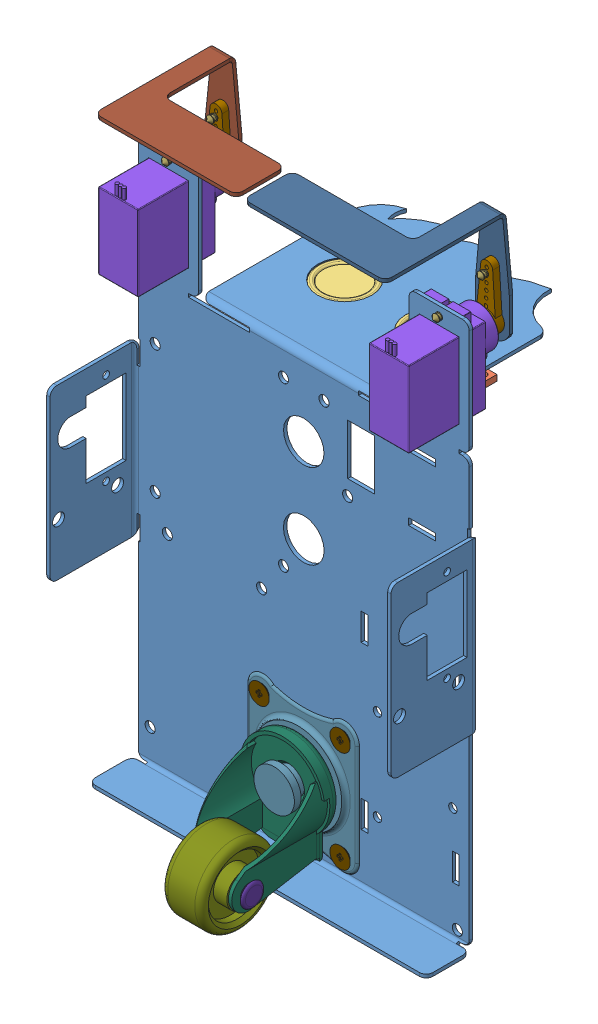
SolidWorks assembly Ensamblaje3, configuration Predeterminado. Lengths in mm.
Overall size (151 194.25 91.61).
41 component instances, 18 part files, 9 mates.
Components (placement in the parent):
- DYOR_MetalSheet_Pusher-1: DYOR_MetalSheet_Pusher [Predeterminado] at (90.3982 -139.1144 139.7994) size (151 194.25 79.67)
- HC-SR04 Ping Sensor-1: HC-SR04 Ping Sensor [Default] at (150.4372 -204.3854 114.6556) x (0 0 -1) z (0 1 0) size (25.18 45 18.07)
  - PCB-1: PCB [Default] at origin size (20.5 45 1.75)
  - Transducer-1: Transducer [Default] at (0 -13.16 13.25) x (1 0 0) z (0 -1 0) size (15.88 12 15.88)
  - Transducer-2: Transducer [Default] at (0 12.34 13.25) x (1 0 0) z (0 -1 0) size (15.88 12 15.88)
  - 3 Pin Header 90 Degree-1: 3 Pin Header 90 Degree [Default] at (8.4275 0 -1.25) x (-1 0 0) z (0 -1 0) size (8 7.82 10)
  - 14 Pin SMT-1: 14 Pin SMT [Default] at (-0.35 -18.5 -0.85) x (0 -1 0) z (1 0 0) size (6 1.6 8.8)
  - 14 Pin SMT-2: 14 Pin SMT [Default] at (0 -0.3826 -0.85) x (1 0 0) z (0 1 0) size (6 1.6 8.8)
  - 14 Pin SMT-3: 14 Pin SMT [Default] at (0 17.5274 -0.85) x (1 0 0) z (0 1 0) size (6 1.6 8.8)
  - Cap1 SMT-1: Cap1 SMT [Default] at (-1.755 7.4774 -0.9689) x (0 1 0) z (-1 0 0) size (4.5 1.84 1.75)
  - Cap1 SMT-2: Cap1 SMT [Default] at (6.835 7.4774 -0.9689) x (0 1 0) z (-1 0 0) size (4.5 1.84 1.75)
  - Cap1 SMT-3: Cap1 SMT [Default] at (-6.835 7.4774 -0.9689) x (0 1 0) z (-1 0 0) size (4.5 1.84 1.75)
  - Cap1 SMT-4: Cap1 SMT [Default] at (4.295 7.4774 -0.9689) x (0 1 0) z (-1 0 0) size (4.5 1.84 1.75)
  - Cap1 SMT-5: Cap1 SMT [Default] at (1.755 7.4774 -0.9689) x (0 1 0) z (-1 0 0) size (4.5 1.84 1.75)
  - Cap1 SMT-6: Cap1 SMT [Default] at (-4.295 7.4774 -0.9689) x (0 1 0) z (-1 0 0) size (4.5 1.84 1.75)
  - HC-SR04 Crystal-1: HC-SR04 Crystal [Default] at (-8.3 0 1.75) x (0 -1 0) z (0 0 1) size (10 3.5 2.7)
- PU-1: PU [Predeterminado] at (-16.2984 3.5 -1.0225) size (91.94 49.57 37.38)
  - sg90-1: sg90 [Default] at (201.5956 -166.7354 155.7219) x (0 -1 0) z (1 0 0) size (31.9 29.9 11.8)
  - sg90-2: sg90 [Default] at (121.452 -166.7354 155.7219) x (0 -1 0) z (1 0 0) size (31.9 29.9 11.8)
  - SG90 plastic Horn-1: SG90 plastic Horn [Default] at (127.352 -172.6354 127.0219) x (0.017141 0.999853 0) z (-0.999853 0.017141 0) size (19.4 4 7.07)
  - SG90 plastic Horn-2: SG90 plastic Horn [Default] at (207.4956 -172.6354 127.0219) x (0.020276 0.999794 0) z (-0.999794 0.020276 0) size (19.4 4 7.07)
  - Pusher_left-1: Pusher_left [Predeterminado] at (252.6438 -158.8738 124.0219) x (-1 0 0) z (0 0 -1) size (44 33.65 35.77)
  - Pusher_right-1: Pusher_right [Predeterminado] at (82.2037 -158.8738 125.0219) size (44 33.65 35.77)
  - M2x6 SelfTap Screw-1: M2x6 SelfTap Screw [Predeterminado] at (207.4956 -164.3354 136.8219) x (-0.923728 -0.383049 0) z (0 0 -1) size (3.4 3.28 6)
  - M2x6 SelfTap Screw-2: M2x6 SelfTap Screw [Predeterminado] at (207.4956 -191.6354 136.3219) x (-0.923728 -0.383049 0) z (0 0 -1) size (3.4 3.28 6)
  - M2x6 SelfTap Screw-3: M2x6 SelfTap Screw [Predeterminado] at (127.352 -164.3354 136.8219) x (-0.993348 0.115149 0) z (0 0 -1) size (3.4 3.28 6)
  - M2x6 SelfTap Screw-4: M2x6 SelfTap Screw [Predeterminado] at (127.352 -191.6354 136.8219) x (-0.923728 -0.383049 0) z (0 0 -1) size (3.4 3.28 6)
  - (M2_3_mm)_90116A007_METRIC 316 SS PAN HEAD PHILLIPS MACHINE SCREW-1: (M2_3_mm)_90116A007_METRIC 316 SS PAN HEAD PHILLIPS MACHINE SCREW [90116A007] at (127.352 -172.6354 127.0219) x (-0.923728 -0.383049 0) z (0 0 -1) size (4 4 4.68)
  - (M2_3_mm)_90116A007_METRIC 316 SS PAN HEAD PHILLIPS MACHINE SCREW-2: (M2_3_mm)_90116A007_METRIC 316 SS PAN HEAD PHILLIPS MACHINE SCREW [90116A007] at (207.4956 -172.6354 127.0219) x (-0.923728 -0.383049 0) z (0 0 -1) size (4 4 4.68)
  - M2x6 SelfTap Screw-5: M2x6 SelfTap Screw [Predeterminado] at (127.352 -160.1354 123.5219) x (-0.923728 -0.383049 0) z (0 0 -1) size (3.4 3.28 6)
  - M2x6 SelfTap Screw-6: M2x6 SelfTap Screw [Predeterminado] at (207.4956 -160.1354 123.5219) x (-0.923728 -0.383049 0) z (0 0 -1) size (3.4 3.28 6)
- CA-1: CA [Predeterminado] at (0 -1.6781 0) size (33 45.94 43.84)
  - Caster Wheel-1: Caster Wheel [Default] at (197.1109 -294.8334 184.5177) x (0 1 0) z (-1 0 0) size (45.94 37.15 33)
    - caster holder-1: caster holder [Default] at (-24.0751 44.7184 29.5137) x (1 0 0) z (0 0 -1) size (39 8.84 33)
    - holder-1: holder [Default] at (-1.5751 42.9484 46.0137) x (0 0 1) z (1 0 0) size (25 28.07 31.31)
    - caster wheel-1: caster wheel [Default] at (-15.6961 19.9484 46.0137) x (0.997275 0.073773 0) z (0 0 1) size (23 23 14)
    - Part4-1: Part4 [Default] at (-15.6961 19.9484 55.0137) x (-0.978448 0.206495 0) z (0 0 -1) size (7 7 20)
  - M4x8 SelfTap Screw-1: M4x8 SelfTap Screw [Predeterminado] at (139.0972 -281.4086 141.0494) size (6 6 8)
  - M4x8 SelfTap Screw-2: M4x8 SelfTap Screw [Predeterminado] at (163.0972 -281.4086 141.0494) size (6 6 8)
  - M4x8 SelfTap Screw-3: M4x8 SelfTap Screw [Predeterminado] at (139.0972 -311.4086 141.0494) size (6 6 8)
  - M4x8 SelfTap Screw-4: M4x8 SelfTap Screw [Predeterminado] at (163.0972 -311.4086 141.0494) size (6 6 8)
Mates (geometry in assembly coordinates):
- Concéntrica259: concentric: circle of HC-SR04 Ping Sensor-1/Transducer-2; circle of DYOR_MetalSheet_Pusher-1
- Paralelo85: parallel: plane of DYOR_MetalSheet_Pusher-1 through (184.2972 -190.1354 138.7994) normal (0 0 -1); plane of HC-SR04 Ping Sensor-1/PCB-1 through (127.9372 -202.6354 124.9056) normal (0 0 1)
- Coincidente413: coincident: plane of DYOR_MetalSheet_Pusher-1 through (184.2972 -190.6354 137.6556) normal (0 1 0); plane of HC-SR04 Ping Sensor-1/Transducer-1 through (163.5972 -190.6354 106.7156) normal (0 1 0)
- Coincidente414: coincident: plane of DYOR_MetalSheet_Pusher-1 through (184.2972 -190.1354 138.7994) normal (0 0 -1); plane of PU-1/sg90-1 through (197.0972 -190.4354 138.7994) normal (0 0 1)
- Concéntrica260: concentric: circle of DYOR_MetalSheet_Pusher-1; circle of PU-1/M2x6 SelfTap Screw-2
- Concéntrica261: concentric: circle of DYOR_MetalSheet_Pusher-1; circle of PU-1/M2x6 SelfTap Screw-1
- Coincidente488: coincident: plane of DYOR_MetalSheet_Pusher-1 through (184.2972 -190.1354 139.7994) normal (0 0 1); plane of CA-1/Caster Wheel-1/caster holder-1 through (151.0972 -253.2884 139.7994) normal (0 0 -1)
- Concéntrica291: concentric: circle of DYOR_MetalSheet_Pusher-1; circle of CA-1/M4x8 SelfTap Screw-2
- Concéntrica292: concentric: circle of DYOR_MetalSheet_Pusher-1; circle of CA-1/M4x8 SelfTap Screw-4
